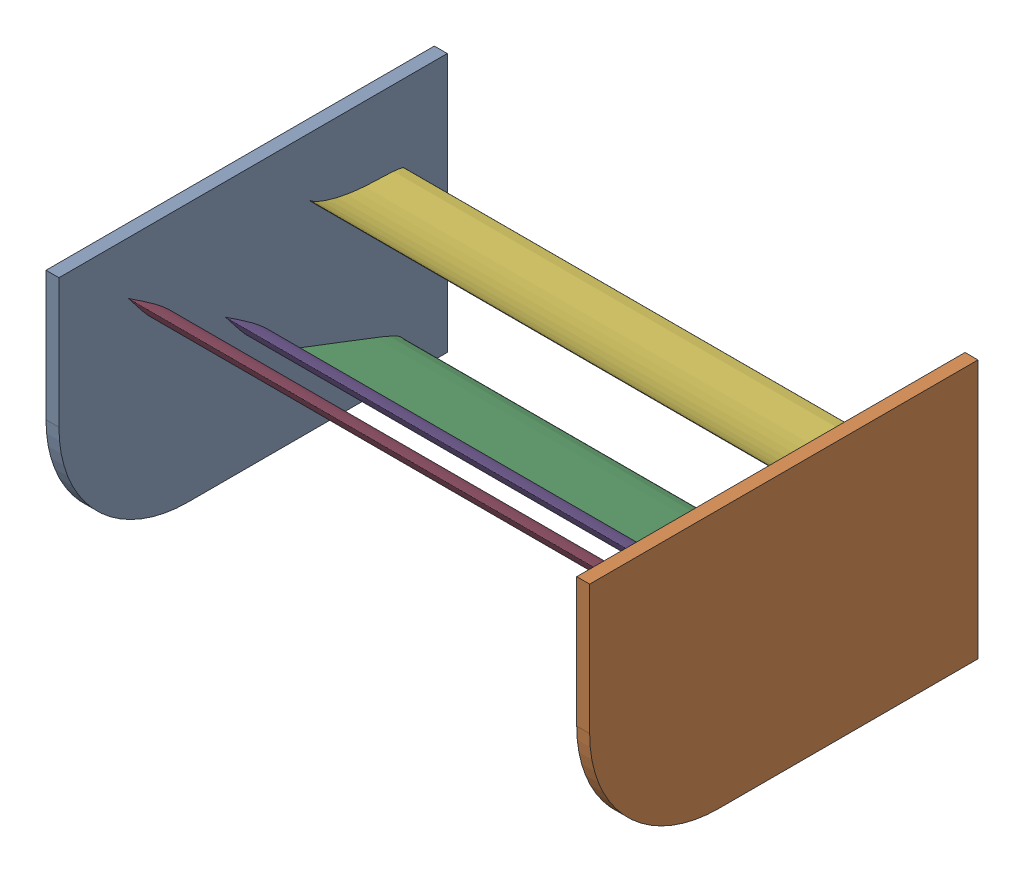
SolidWorks assembly rear-wing_assy, configuration Default. Lengths in mm.
Overall size (420 200 300).
6 component instances, 5 part files, 15 mates.
Components (placement in the parent):
- endplate_L-1: endplate_L [Default] x (0 0 1) z (-1 0 0) size (300 200 10)
- endplate_R-1: endplate_R [Default] at (410 0 0) x (0 0 1) z (-1 0 0) size (300 200 10)
- clark-y-1: clark-y [Default] at (205 26.0318 35.2619) x (0 0.390731 0.920505) z (1 0 0) size (100.02 12.19 410)
- s8037-1: s8037 [Default] at (205 127.1195 208.0256) x (0 0.642788 0.766044) z (1 0 0) size (50.08 8.01 410)
- s8037-2: s8037 [Default] at (205 77.1195 133.0256) x (0 0.642788 0.766044) z (1 0 0) size (50.08 8.01 410)
- s1223-1: s1223 [Default] at (205 139.5047 33.5753) x (0 0.213204 0.977008) z (1 0 0) size (75.08 11.35 410)
Mates (geometry in assembly coordinates):
- Parallel1: parallel anti-aligned: plane of endplate_L-1 through (-5 100 200) normal (-1 0 0); plane of endplate_R-1 through (415 100 200) normal (1 0 0)
- Coincident2: coincident aligned: plane of endplate_L-1 through (-5 200 300) normal (0 0 1); plane of endplate_R-1 through (415 200 300) normal (0 0 1)
- Coincident3: coincident aligned: plane of endplate_L-1 through (-5 200 0) normal (0 1 0); plane of endplate_R-1 through (415 200 0) normal (0 1 0)
- Concentric1: concentric aligned: cylinder of endplate_L-1 through (0 40 75) axis (1 0 0) radius 2.5; cylinder of clark-y-1 through (0 40 75) axis (1 0 0) radius 3
- Width1: width aligned: plane of endplate_L-1 through (5 100 200) normal (1 0 0); plane of endplate_R-1 through (405 100 200) normal (-1 0 0); plane of clark-y-1 through (405 25.3496 36.0174) normal (1 0 0); plane of clark-y-1 through (5 25.3496 36.0174) normal (-1 0 0)
- Coincident4: coincident anti-aligned: plane of endplate_L-1 through (5 100 200) normal (1 0 0); plane of clark-y-1 through (5 25.3496 36.0174) normal (-1 0 0)
- Width2: width aligned: plane of s8037-2 through (405 76.7254 133.623) normal (1 0 0); plane of s8037-2 through (5 76.7254 133.623) normal (-1 0 0); plane of endplate_L-1 through (5 100 200) normal (1 0 0); plane of endplate_R-1 through (405 100 200) normal (-1 0 0)
- Concentric2: concentric anti-aligned: cylinder of endplate_R-1 through (410 90 150) axis (-1 0 0) radius 2.5; cylinder of s8037-2 through (0 90 150) axis (1 0 0) radius 2.5
- Width3: width aligned: plane of s8037-1 through (405 126.7254 208.623) normal (1 0 0); plane of s8037-1 through (5 126.7254 208.623) normal (-1 0 0); plane of endplate_R-1 through (405 100 200) normal (-1 0 0); plane of endplate_L-1 through (5 100 200) normal (1 0 0)
- Concentric3: concentric anti-aligned: cylinder of endplate_R-1 through (410 140 225) axis (-1 0 0) radius 2.5; cylinder of s8037-1 through (0 140 225) axis (1 0 0) radius 2.5
- Angle1: planar angle = 0.698132 rad aligned: line of s8037-2 through (205 77.1195 133.0256) axis (0 0.642788 0.766044); line of endplate_L-1 through (5 0 0) axis (0 0 1)
- Angle2: planar angle = 0.401426 rad aligned: line of clark-y-1 through (205 26.0318 35.2619) axis (0 0.390731 0.920505); line of endplate_L-1 through (5 0 0) axis (0 0 1)
- Angle3: planar angle = 0.698132 rad aligned: line of s8037-1 through (205 127.1195 208.0256) axis (0 0.642788 0.766044); line of endplate_L-1 through (5 0 0) axis (0 0 1)
- Concentric4: concentric aligned: cylinder of endplate_R-1 through (410 140 60) axis (-1 0 0) radius 2.5; cylinder of s1223-1 through (422.0711 140 60) axis (-1 0 0) radius 2.5
- Width4: width aligned: plane of s1223-1 through (405 137.9733 34.3705) normal (1 0 0); plane of endplate_L-1 through (5 137.9733 34.3705) normal (-1 0 0); plane of s1223-1 through (5 100 200) normal (1 0 0); plane of endplate_R-1 through (405 100 200) normal (-1 0 0)
